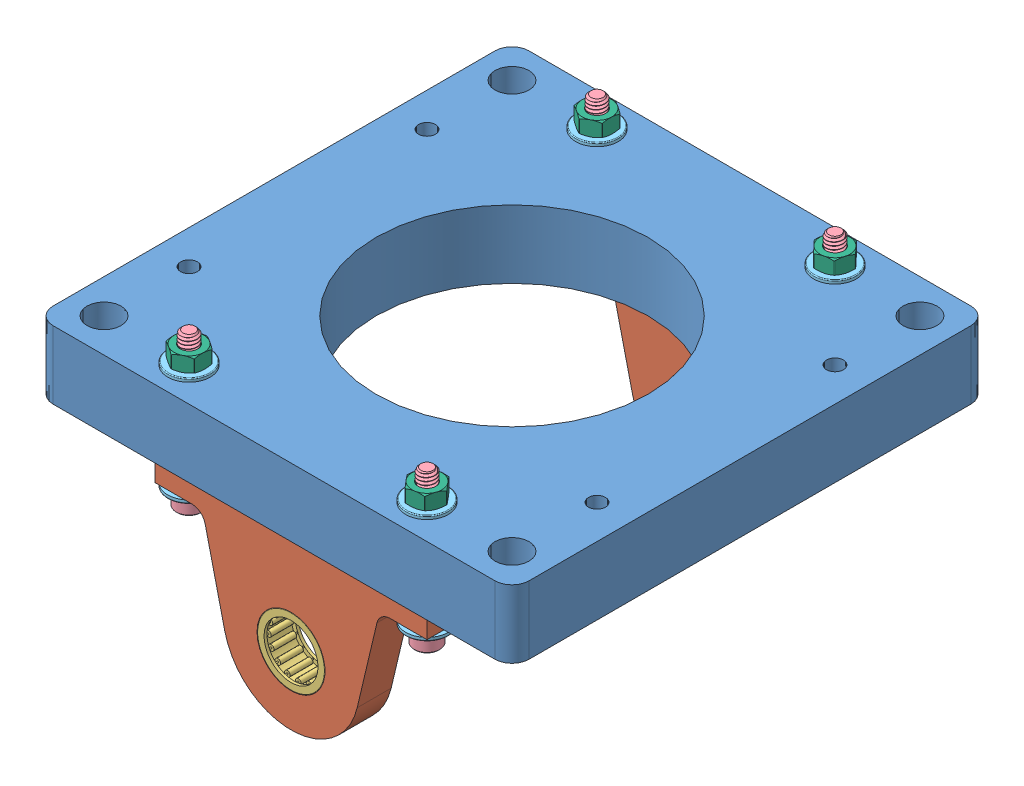
SolidWorks assembly Intermediate Ring with Brackets, configuration Default. Lengths in mm.
Overall size (177.8 104.64 177.8).
27 component instances, 6 part files, 12 mates.
Components (placement in the parent):
- Intermediate Ring-2: Intermediate Ring [Default] at (-88.8543 79.5311 225.6413) size (177.8 25.4 177.8)
- Crosstree Bracket Assembly-1: Crosstree Bracket Assembly [Default] at (-114.4432 107.4664 379.2209) x (1 0 0) z (0 0 -1) size (104.78 104.64 15.88)
  - Crosstree Bracket-1: Crosstree Bracket [Default] at (25.5889 69.8453 71.0296) size (101.6 67.31 12.7)
  - 5905K26_Needle-Roller Bearing-1: 5905K26_Needle-Roller Bearing [5905K26] at (25.5889 69.8453 77.3796) x (-0.328056 0.944658 0) z (0 0 1) size (25.4 25.4 12.7)
  - 90128A253_Zinc-Plated Alloy Steel Socket Head Screw-1: 90128A253_Zinc-Plated Alloy Steel Socket Head Screw [90128A253] at (-18.8611 19.6803 77.3796) x (-0.333308 0 0.942818) z (0 1 0) size (9.53 9.53 57.93)
  - 90107A029_316 Stainless Steel Washer-2: 90107A029_316 Stainless Steel Washer [90107A029] at (-18.8611 41.2703 77.3796) x (1 0 0) z (0 1 0) size (15.88 15.88 1.27)
  - 90128A253_Zinc-Plated Alloy Steel Socket Head Screw-2: 90128A253_Zinc-Plated Alloy Steel Socket Head Screw [90128A253] at (70.0389 19.6803 77.3796) x (1 0 0) z (0 1 0) size (9.53 9.53 57.93)
  - 90107A029_316 Stainless Steel Washer-3: 90107A029_316 Stainless Steel Washer [90107A029] at (70.0389 41.2703 77.3796) x (1 0 0) z (0 1 0) size (15.88 15.88 1.27)
- Crosstree Bracket Assembly-2: Crosstree Bracket Assembly [Default] at (-114.4432 107.4664 226.8209) x (1 0 0) z (0 0 -1) size (104.78 104.64 15.88)
  - Crosstree Bracket-1: Crosstree Bracket [Default] at (25.5889 69.8453 71.0296) size (101.6 67.31 12.7)
  - 5905K26_Needle-Roller Bearing-1: 5905K26_Needle-Roller Bearing [5905K26] at (25.5889 69.8453 77.3796) x (-0.328056 0.944658 0) z (0 0 1) size (25.4 25.4 12.7)
  - 90128A253_Zinc-Plated Alloy Steel Socket Head Screw-1: 90128A253_Zinc-Plated Alloy Steel Socket Head Screw [90128A253] at (-18.8611 19.6803 77.3796) x (-0.333308 0 0.942818) z (0 1 0) size (9.53 9.53 57.93)
  - 90107A029_316 Stainless Steel Washer-2: 90107A029_316 Stainless Steel Washer [90107A029] at (-18.8611 41.2703 77.3796) x (1 0 0) z (0 1 0) size (15.88 15.88 1.27)
  - 90128A253_Zinc-Plated Alloy Steel Socket Head Screw-2: 90128A253_Zinc-Plated Alloy Steel Socket Head Screw [90128A253] at (70.0389 19.6803 77.3796) x (1 0 0) z (0 1 0) size (9.53 9.53 57.93)
  - 90107A029_316 Stainless Steel Washer-3: 90107A029_316 Stainless Steel Washer [90107A029] at (70.0389 41.2703 77.3796) x (1 0 0) z (0 1 0) size (15.88 15.88 1.27)
- 1_4_20_Nut Washer Assembly-1: 1_4_20_Nut Washer Assembly [Default] at (-68.2154 77.2758 126.5121) x (0.004746 0 -0.999989) z (0 1 0) size (15.88 15.88 7.21)
  - 90107A029_316 Stainless Steel Washer-1: 90107A029_316 Stainless Steel Washer [90107A029] at (-22.8159 -23.9196 28.2903) size (15.88 15.88 1.27)
  - 95462A029_Medium-Strength Steel Hex Nut-1: 95462A029_Medium-Strength Steel Hex Nut [95462A029] at (-22.8159 -23.9196 31.7034) x (0.972065 0.23471 0) z (0 0 1) size (11.11 12.75 6.32)
- 1_4_20_Nut Washer Assembly-2: 1_4_20_Nut Washer Assembly [Default] at (-104.6077 77.2758 165.8492) x (0.240016 0 0.970769) z (0 1 0) size (15.88 15.88 7.21)
  - 90107A029_316 Stainless Steel Washer-1: 90107A029_316 Stainless Steel Washer [90107A029] at (-22.8159 -23.9196 28.2903) size (15.88 15.88 1.27)
  - 95462A029_Medium-Strength Steel Hex Nut-1: 95462A029_Medium-Strength Steel Hex Nut [95462A029] at (-22.8159 -23.9196 31.7034) x (0.972065 0.23471 0) z (0 0 1) size (11.11 12.75 6.32)
- 1_4_20_Nut Washer Assembly-3: 1_4_20_Nut Washer Assembly [Default] at (-104.6027 77.2758 318.2405) x (0.240311 0 0.970696) z (0 1 0) size (15.88 15.88 7.21)
  - 90107A029_316 Stainless Steel Washer-1: 90107A029_316 Stainless Steel Washer [90107A029] at (-22.8159 -23.9196 28.2903) size (15.88 15.88 1.27)
  - 95462A029_Medium-Strength Steel Hex Nut-1: 95462A029_Medium-Strength Steel Hex Nut [95462A029] at (-22.8159 -23.9196 31.7034) x (0.972065 0.23471 0) z (0 0 1) size (11.11 12.75 6.32)
- 1_4_20_Nut Washer Assembly-4: 1_4_20_Nut Washer Assembly [Default] at (-34.5945 77.2758 270.2742) x (0.895836 0 -0.444384) z (0 1 0) size (15.88 15.88 7.21)
  - 90107A029_316 Stainless Steel Washer-1: 90107A029_316 Stainless Steel Washer [90107A029] at (-22.8159 -23.9196 28.2903) size (15.88 15.88 1.27)
  - 95462A029_Medium-Strength Steel Hex Nut-1: 95462A029_Medium-Strength Steel Hex Nut [95462A029] at (-22.8159 -23.9196 31.7034) x (0.972065 0.23471 0) z (0 0 1) size (11.11 12.75 6.32)
Mates (geometry in assembly coordinates):
- Coincident1: coincident anti-aligned: circle of Intermediate Ring-2; circle of Crosstree Bracket Assembly-1/Crosstree Bracket-1
- Coincident2: coincident anti-aligned: circle of Intermediate Ring-2; circle of Crosstree Bracket Assembly-1/Crosstree Bracket-1
- Coincident3: coincident anti-aligned: circle of Intermediate Ring-2; circle of Crosstree Bracket Assembly-2/Crosstree Bracket-1
- Coincident4: coincident anti-aligned: circle of Intermediate Ring-2; circle of Crosstree Bracket Assembly-2/Crosstree Bracket-1
- Concentric1: concentric aligned: circle of Intermediate Ring-2; circle of 1_4_20_Nut Washer Assembly-1/90107A029_316 Stainless Steel Washer-1
- Concentric2: concentric anti-aligned: cylinder of Intermediate Ring-2; cylinder of 1_4_20_Nut Washer Assembly-2/90107A029_316 Stainless Steel Washer-1 through (-133.3043 106.2011 149.4413) axis (0 -1 0) radius 3.5687
- Coincident6: coincident anti-aligned: plane of Intermediate Ring-2 through (-88.8543 104.9311 225.6413) normal (0 1 0); plane of 1_4_20_Nut Washer Assembly-2/90107A029_316 Stainless Steel Washer-1 through (-133.3043 104.9311 149.4413) normal (0 -1 0)
- Concentric3: concentric aligned: circle of Intermediate Ring-2; circle of 1_4_20_Nut Washer Assembly-3/90107A029_316 Stainless Steel Washer-1
- Coincident7: coincident anti-aligned: plane of Intermediate Ring-2 through (-88.8543 104.9311 225.6413) normal (0 1 0); plane of 1_4_20_Nut Washer Assembly-3/90107A029_316 Stainless Steel Washer-1 through (-133.3043 104.9311 301.8413) normal (0 -1 0)
- Concentric4: concentric aligned: circle of Intermediate Ring-2; circle of 1_4_20_Nut Washer Assembly-4/90107A029_316 Stainless Steel Washer-1
- Coincident8: coincident anti-aligned: plane of Intermediate Ring-2 through (-88.8543 104.9311 225.6413) normal (0 1 0); plane of 1_4_20_Nut Washer Assembly-4/90107A029_316 Stainless Steel Washer-1 through (-44.4043 104.9311 301.8413) normal (0 -1 0)
- Coincident11: coincident anti-aligned: plane of 1_4_20_Nut Washer Assembly-1/90107A029_316 Stainless Steel Washer-1 through (-44.4043 104.9311 149.4413) normal (0 -1 0); plane of Intermediate Ring-2 through (-88.8543 104.9311 225.6413) normal (0 1 0)
